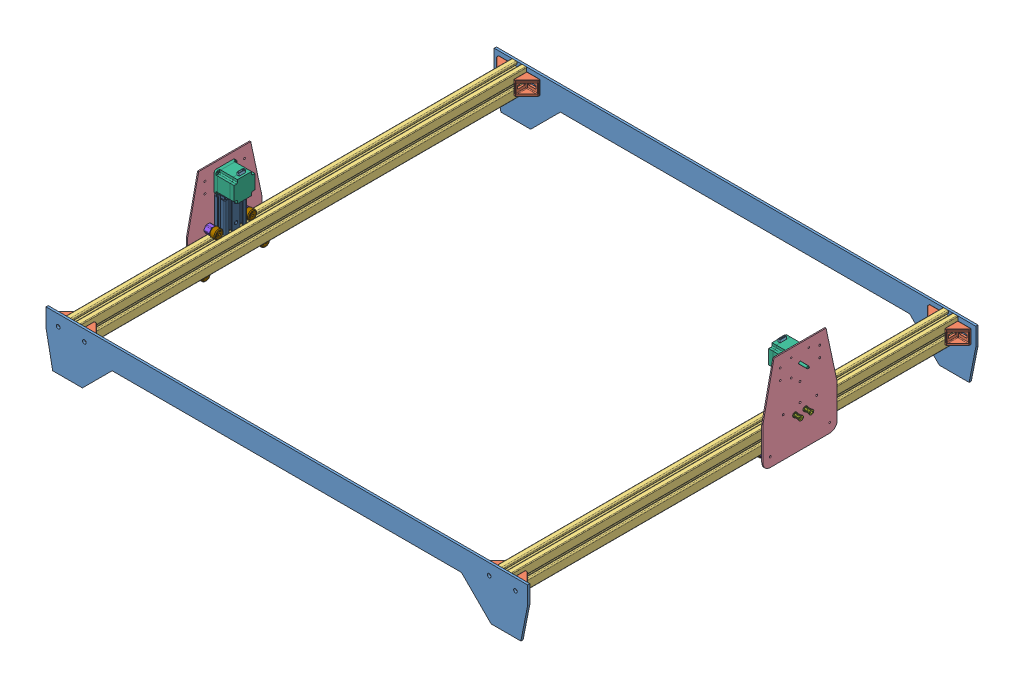
SolidWorks assembly base ensamble, configuration Predeterminado. Lengths in mm.
Overall size (1296.27 294.43 1212).
44 component instances, 10 part files, 17 mates.
Components (placement in the parent):
- patas base-1: patas base [Predeterminado] at (38.6537 65.539 1293) size (1296 140 6)
- patas base-2: patas base [Predeterminado] at (38.3817 65.539 2499) size (1296 140 6)
- escuadra-1: escuadra [Predeterminado] at (-579.6459 66.5998 2481) x (-1 0 0) z (0 1 0) size (36 36 38.2)
- escuadra-2: escuadra [Predeterminado] at (-503.6459 65.8615 2481) x (1 0 0) z (0 -1 0) size (36 36 38.2)
- escuadra-3: escuadra [Predeterminado] at (580.3743 66.5126 2481) x (-1 0 0) z (0 1 0) size (36 36 38.2)
- escuadra-4: escuadra [Predeterminado] at (656.3637 65.6666 2481) x (1 0 0) z (0 -1 0) size (36 36 38.2)
- escuadra-10: escuadra [Predeterminado] at (-503.6459 65.9894 1317) x (0 0 1) z (0 -1 0) size (36 36 38.2)
- escuadra-11: escuadra [Predeterminado] at (656.3743 65.3817 1317) x (0 0 1) z (0 -1 0) size (36 36 38.2)
- escuadra-12: escuadra [Predeterminado] at (-579.6459 65.6649 1317) x (0 0 1) z (0 1 0) size (36 36 38.2)
- escuadra-13: escuadra [Predeterminado] at (580.3637 65.7306 1317) x (0 0 1) z (0 1 0) size (36 36 38.2)
- ensamble eje x-1: ensamble eje x [Predeterminado] at (627.0482 69.385 699) size (77.3 250 1200)
  - perfil120_v1-1: perfil120_v1 [Predeterminado] at (-8.6844 -3.846 600) size (40 60 1200)
  - soporteEjeX-1: soporteEjeX [Predeterminado] at (13.9188 134.7858 1030.3113) x (0 0 -1) z (1 0 0) size (200 250 3)
  - MotorStepper-1: MotorStepper [Predeterminado] at (-13.2162 160.9965 1030.6978) x (0 0 1) z (-1 0 0) size (56.4 63.4 77.3)
    - JST XH 6 S6B-XH-A1 shrouded header connector-3: JST XH 6 S6B-XH-A1 shrouded header connector [Default] at (-0.3865 1.9892 17.54) size (17.54 10.45 5.75)
    - tapa-3: tapa [Predeterminado] at (-0.3865 -26.2108 -27.135) size (56.4 56.4 77.3)
  - poleaLoca_prueba-1: poleaLoca_prueba [Predeterminado] at (24.4188 21.0858 1016.3113) x (0 0 -1) z (-1 0 0) size (12 12 17)
  - poleaLoca_prueba-2: poleaLoca_prueba [Predeterminado] at (24.4188 21.0858 1044.3113) x (0 0 -1) z (-1 0 0) size (12 12 17)
  - espaciador-1: espaciador [Predeterminado] at (-0.8812 36.3858 985.3113) x (0 0 -1) z (1 0 0) size (22.17 20.07 14.8)
  - espaciador-2: espaciador [Predeterminado] at (-0.8812 36.3858 1075.3113) x (0 0 -1) z (1 0 0) size (22.17 20.07 14.8)
  - espaciador-3: espaciador [Predeterminado] at (-0.8812 -44.2142 1110.3113) x (0 0 -1) z (1 0 0) size (22.17 20.07 14.8)
  - espaciador-4: espaciador [Predeterminado] at (-0.8812 -44.2142 950.3113) x (0 0 -1) z (1 0 0) size (22.17 20.07 14.8)
  - rueda solida tipo v-6: rueda solida tipo v [Predeterminado] at (-8.8812 36.3858 1075.3113) size (16.1 24 24)
  - rueda solida tipo v-7: rueda solida tipo v [Predeterminado] at (-8.8812 36.3858 985.3113) size (16.1 24 24)
  - rueda solida tipo v-8: rueda solida tipo v [Predeterminado] at (-8.8812 -44.2142 950.3113) size (16.1 24 24)
  - rueda solida tipo v-9: rueda solida tipo v [Predeterminado] at (-8.8812 -44.2142 1110.3113) size (16.1 24 24)
  - perfil_soporte_motor-1: perfil_soporte_motor [Predeterminado] at (-1.5478 106.5858 1030.0113) x (1 0 0) z (0 -1 0) size (30.1 60.1 80)
- ensamble eje x-2: ensamble eje x [Predeterminado] at (-551.0433 69.385 3099) x (-1 0 0) z (0 0 -1) size (77.3 250 1200)
  - perfil120_v1-1: perfil120_v1 [Predeterminado] at (-8.6844 -3.846 600) size (40 60 1200)
  - soporteEjeX-1: soporteEjeX [Predeterminado] at (13.9188 134.7858 1030.3113) x (0 0 -1) z (1 0 0) size (200 250 3)
  - MotorStepper-1: MotorStepper [Predeterminado] at (-13.2162 160.9965 1030.6978) x (0 0 1) z (-1 0 0) size (56.4 63.4 77.3)
    - JST XH 6 S6B-XH-A1 shrouded header connector-3: JST XH 6 S6B-XH-A1 shrouded header connector [Default] at (-0.3865 1.9892 17.54) size (17.54 10.45 5.75)
    - tapa-3: tapa [Predeterminado] at (-0.3865 -26.2108 -27.135) size (56.4 56.4 77.3)
  - poleaLoca_prueba-1: poleaLoca_prueba [Predeterminado] at (24.4188 21.0858 1016.3113) x (0 0 -1) z (-1 0 0) size (12 12 17)
  - poleaLoca_prueba-2: poleaLoca_prueba [Predeterminado] at (24.4188 21.0858 1044.3113) x (0 0 -1) z (-1 0 0) size (12 12 17)
  - espaciador-1: espaciador [Predeterminado] at (-0.8812 36.3858 985.3113) x (0 0 -1) z (1 0 0) size (22.17 20.07 14.8)
  - espaciador-2: espaciador [Predeterminado] at (-0.8812 36.3858 1075.3113) x (0 0 -1) z (1 0 0) size (22.17 20.07 14.8)
  - espaciador-3: espaciador [Predeterminado] at (-0.8812 -44.2142 1110.3113) x (0 0 -1) z (1 0 0) size (22.17 20.07 14.8)
  - espaciador-4: espaciador [Predeterminado] at (-0.8812 -44.2142 950.3113) x (0 0 -1) z (1 0 0) size (22.17 20.07 14.8)
  - rueda solida tipo v-6: rueda solida tipo v [Predeterminado] at (-8.8812 36.3858 1075.3113) size (16.1 24 24)
  - rueda solida tipo v-7: rueda solida tipo v [Predeterminado] at (-8.8812 36.3858 985.3113) size (16.1 24 24)
  - rueda solida tipo v-8: rueda solida tipo v [Predeterminado] at (-8.8812 -44.2142 950.3113) size (16.1 24 24)
  - rueda solida tipo v-9: rueda solida tipo v [Predeterminado] at (-8.8812 -44.2142 1110.3113) size (16.1 24 24)
  - perfil_soporte_motor-1: perfil_soporte_motor [Predeterminado] at (-1.5478 106.5858 1030.0113) x (1 0 0) z (0 -1 0) size (30.1 60.1 80)
Mates (geometry in assembly coordinates):
- Coincidente8: coincident anti-aligned: plane of patas base-2 through (38.3817 65.539 2499) normal (0 0 -1); plane of escuadra-4 through (656.3637 84.7666 2499) normal (0 0 1)
- Coincidente9: coincident anti-aligned: plane of patas base-2 through (38.3817 65.539 2499) normal (0 0 -1); plane of escuadra-3 through (580.3743 47.4126 2499) normal (0 0 1)
- Coincidente11: coincident anti-aligned: plane of patas base-2 through (38.3817 65.539 2499) normal (0 0 -1); plane of escuadra-2 through (-503.6459 84.9615 2499) normal (0 0 1)
- Coincidente13: coincident anti-aligned: plane of patas base-2 through (38.3817 65.539 2499) normal (0 0 -1); plane of escuadra-1 through (-579.6459 47.4998 2499) normal (0 0 1)
- Coincidente15: coincident anti-aligned: plane of patas base-1 through (38.6537 65.539 1299) normal (0 0 1); plane of escuadra-10 through (-503.6459 85.0894 1299) normal (0 0 -1)
- Coincidente17: coincident anti-aligned: plane of patas base-1 through (38.6537 65.539 1299) normal (0 0 1); plane of escuadra-12 through (-579.6459 46.5649 1299) normal (0 0 -1)
- Coincidente19: coincident anti-aligned: plane of patas base-1 through (38.6537 65.539 1299) normal (0 0 1); plane of escuadra-11 through (656.3743 84.4817 1299) normal (0 0 -1)
- Coincidente22: coincident anti-aligned: plane of patas base-1 through (38.6537 65.539 1299) normal (0 0 1); plane of escuadra-13 through (580.3637 46.6306 1299) normal (0 0 -1)
- Coincidente24: coincident anti-aligned: plane of patas base-2 through (38.3817 65.539 2499) normal (0 0 -1); plane of ensamble eje x-1/perfil120_v1-1 through (618.3637 65.539 2499) normal (0 0 1)
- Coincidente25: coincident anti-aligned: plane of escuadra-4 through (638.3637 84.7666 2481) normal (-1 0 0); plane of ensamble eje x-1/perfil120_v1-1 through (638.3637 70.754 2499) normal (1 0 0)
- Coincidente26: coincident aligned: line of patas base-2 through (686.3817 95.539 2499) axis (-1 0 0); line of ensamble eje x-1/perfil120_v1-1 through (610.1637 95.539 2499) axis (-1 0 0)
- Coincidente27: coincident anti-aligned: plane of patas base-1 through (38.6537 65.539 1299) normal (0 0 1); plane of ensamble eje x-1/perfil120_v1-1 through (618.3637 65.539 1299) normal (0 0 -1)
- Coincidente28: coincident anti-aligned: plane of escuadra-13 through (598.3637 46.6306 1317) normal (1 0 0); plane of ensamble eje x-1/perfil120_v1-1 through (598.3637 70.754 2499) normal (-1 0 0)
- Coincidente29: coincident aligned: line of patas base-1 through (686.6537 95.539 1299) axis (-1 0 0); line of ensamble eje x-1/perfil120_v1-1 through (610.1637 95.539 1299) axis (-1 0 0)
- Coincidente36: coincident anti-aligned: plane of patas base-2 through (38.3817 65.539 2499) normal (0 0 -1); plane of ensamble eje x-2/perfil120_v1-1 through (-542.3589 65.539 2499) normal (0 0 1)
- Coincidente37: coincident anti-aligned: plane of patas base-1 through (38.6537 65.539 1299) normal (0 0 1); plane of ensamble eje x-2/perfil120_v1-1 through (-542.3589 65.539 1299) normal (0 0 -1)
- Coincidente44: coincident anti-aligned: line of patas base-1 through (686.6537 95.539 1299) axis (-1 0 0); line of ensamble eje x-2/perfil120_v1-1 through (-560.3589 95.539 1299) axis (1 0 0)
